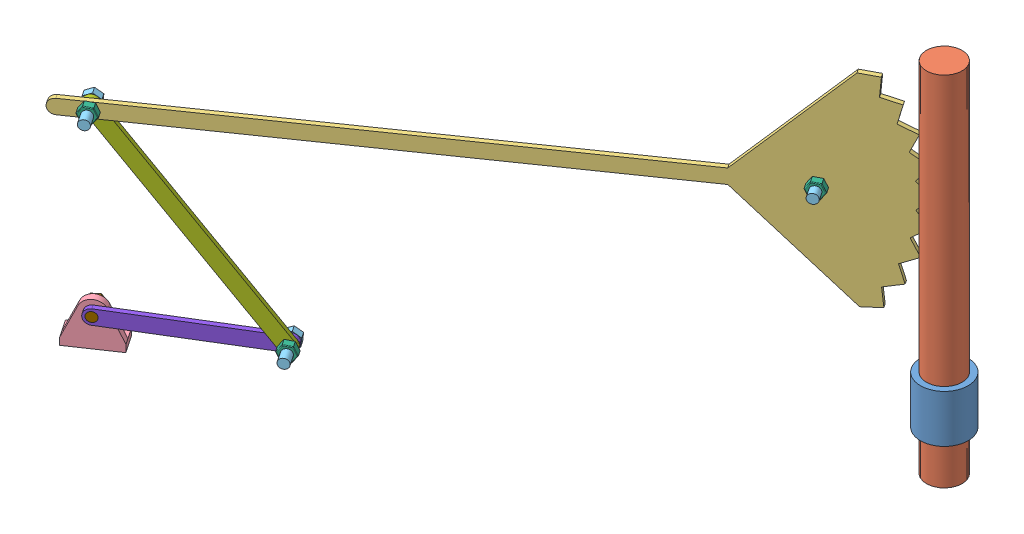
SolidWorks assembly 插齿机, configuration 默认. Lengths in mm.
Overall size (240.39 150 164.35).
14 component instances, 9 part files, 25 mates.
Components (placement in the parent):
- 轴承-1: 轴承 [默认] at (3.8746 0.457 0) size (20 20 20)
- 锤-1: 锤 [默认] at (0.769 48.5886 2.1018) x (0.828161 0 -0.560491) z (0.560491 0 0.828161) size (15 150 15)
- 齿轮杆-1: 齿轮杆 [默认] at (-166.317 72.2583 115.1839) x (0.828127 0.009016 -0.560468) z (0.560491 0 0.828161) size (268 84.85 2)
- 支座4-1: 支座4 [默认] at (-28.3419 73.7666 20.5963) x (-0.828161 0 0.560491) z (-0.560491 0 -0.828161) size (20 18 9)
- 螺钉4,12-1: 螺钉4,12 [默认] at (-30.0233 73.7666 18.1118) x (-0.828161 0 0.560491) z (-0.560491 0 -0.828161) size (6.28 6.9 15)
- 螺母4-1: 螺母4 [默认] at (-27.2209 73.7666 22.2526) x (0.828161 0 -0.560491) z (0.560491 0 0.828161) size (6.9 6.3 3)
- 杆100-1: 杆100 [默认] at (-185.8528 30.2022 124.7831) x (0.496542 -0.800321 -0.336054) z (0.560491 0 0.828161) size (106 6 2)
- 杆60-1: 杆60 [默认] at (-175.7228 -7.7374 115.5122) x (0.827693 -0.033592 -0.560174) z (0.560491 0 0.828161) size (66 6 2)
- 螺钉4,12-2: 螺钉4,12 [默认] at (-211.6508 71.7831 142.2429) x (-0.828161 0 0.560491) z (-0.560491 0 -0.828161) size (6.28 6.9 15)
- 螺母4-2: 螺母4 [默认] at (-209.4088 71.7831 145.5555) x (0.828161 0 -0.560491) z (0.560491 0 0.828161) size (6.9 6.3 3)
- 螺母4-3: 螺母4 [默认] at (-160.8756 -8.249 110.2938) x (0.828151 0.004901 -0.560484) z (0.560491 0 0.828161) size (6.9 6.3 3)
- 螺钉4,12-3: 螺钉4,12 [默认] at (-163.1176 -8.249 106.9811) x (-0.828161 0 0.560491) z (-0.560491 0 -0.828161) size (6.28 6.9 15)
- 支座4-2: 支座4 [默认] at (-212.7792 -6.2334 140.5916) x (-0.828161 0 0.560491) z (-0.560491 0 -0.828161) size (20 18 9)
- 螺钉4-3-1: 螺钉4-3 [默认] at (-214.4607 -6.2334 138.1071) x (-0.828161 0 0.560491) z (-0.560491 0 -0.828161) size (6.91 6.21 8)
Mates (geometry in assembly coordinates):
- 同心1: concentric: cylinder of 轴承-1 through (3.8746 10.457 0) axis (0 -1 0) radius 7.5; cylinder of 锤-1 through (3.8746 123.5886 0) axis (0 1 0) radius 7.5
- 重合1: coincident: plane of 锤-1 through (0.769 48.5886 2.1018) normal (0.560491 0 0.828161); plane of 齿轮杆-1 through (-166.317 72.2583 115.1839) normal (0.560491 0 0.828161)
- 重合3: coincident: line of 锤-1 through (1.2437 74.0886 0.5731) axis (0.560491 0 0.828161); plane of 齿轮杆-1
- 重合4: coincident: plane of 齿轮杆-1 through (-109.0476 -133.0111 75.2171) normal (-0.560491 0 -0.828161); plane of 支座4-1 through (-28.3419 73.7666 20.5963) normal (0.560491 0 0.828161)
- 同心2: concentric: cylinder of 支座4-1 through (-30.0233 73.7666 18.1118) axis (0.560491 0 0.828161) radius 2; cylinder of 螺钉4,12-1 through (-23.2974 73.7666 28.0497) axis (-0.560491 0 -0.828161) radius 2
- 同心3: concentric: cylinder of 齿轮杆-1 through (-27.2209 73.7666 22.2526) axis (-0.560491 0 -0.828161) radius 2; cylinder of 螺钉4,12-1 through (-23.2974 73.7666 28.0497) axis (-0.560491 0 -0.828161) radius 2
- 重合5: coincident: plane of 支座4-1 through (-30.0233 73.7666 18.1118) normal (-0.560491 0 -0.828161); plane of 螺钉4,12-1 through (-30.2711 70.3154 18.2795) normal (0.560491 0 0.828161)
- 重合6: coincident: plane of 齿轮杆-1 through (-107.9266 -133.0111 76.8734) normal (0.560491 0 0.828161); plane of 螺母4-1 through (-26.0302 70.6149 21.4468) normal (-0.560491 0 -0.828161)
- 同心4: concentric: cylinder of 螺钉4,12-1 through (-23.2974 73.7666 28.0497) axis (-0.560491 0 -0.828161) radius 2; cylinder of 螺母4-1 through (-25.5394 73.7666 24.7371) axis (-0.560491 0 -0.828161) radius 2
- 重合7: coincident: plane of 齿轮杆-1 through (-109.0476 -133.0111 75.2171) normal (-0.560491 0 -0.828161); plane of 杆100-1 through (-210.5298 71.7831 143.8992) normal (0.560491 0 0.828161)
- 重合8: coincident: plane of 杆100-1 through (-211.6508 71.7831 142.2429) normal (-0.560491 0 -0.828161); plane of 杆60-1 through (-211.6582 -6.2334 142.2479) normal (0.560491 0 0.828161)
- 同心5: concentric: cylinder of 杆100-1 through (-210.5298 71.7831 143.8992) axis (-0.560491 0 -0.828161) radius 2; cylinder of 螺钉4,12-2 through (-204.9249 71.7831 152.1808) axis (-0.560491 0 -0.828161) radius 2
- 同心6: concentric: cylinder of 齿轮杆-1 through (-209.4088 71.7831 145.5555) axis (-0.560491 0 -0.828161) radius 2; cylinder of 螺钉4,12-2 through (-204.9249 71.7831 152.1808) axis (-0.560491 0 -0.828161) radius 2
- 重合9: coincident: plane of 杆100-1 through (-211.6508 71.7831 142.2429) normal (-0.560491 0 -0.828161); plane of 螺钉4,12-2 through (-211.8986 68.3319 142.4106) normal (0.560491 0 0.828161)
- 重合10: coincident: plane of 齿轮杆-1 through (-107.9266 -133.0111 76.8734) normal (0.560491 0 0.828161); plane of 螺母4-2 through (-208.2182 68.6314 144.7497) normal (-0.560491 0 -0.828161)
- 同心7: concentric: cylinder of 螺钉4,12-2 through (-204.9249 71.7831 152.1808) axis (-0.560491 0 -0.828161) radius 2; cylinder of 螺母4-2 through (-207.7274 71.7831 148.04) axis (-0.560491 0 -0.828161) radius 2
- 同心8: concentric: cylinder of 杆60-1 through (-161.9966 -8.249 108.6374) axis (-0.560491 0 -0.828161) radius 2; cylinder of 螺钉4,12-3 through (-156.3917 -8.249 116.919) axis (-0.560491 0 -0.828161) radius 2
- 同心9: concentric: cylinder of 杆100-1 through (-160.8756 -8.249 110.2938) axis (-0.560491 0 -0.828161) radius 2; cylinder of 螺钉4,12-3 through (-156.3917 -8.249 116.919) axis (-0.560491 0 -0.828161) radius 2
- 重合11: coincident: plane of 杆60-1 through (-212.7792 -6.2334 140.5916) normal (-0.560491 0 -0.828161); plane of 螺钉4,12-3 through (-163.3654 -11.7001 107.1488) normal (0.560491 0 0.828161)
- 同心10: concentric: cylinder of 螺母4-3 through (-159.1942 -8.249 112.7782) axis (-0.560491 0 -0.828161) radius 2; cylinder of 螺钉4,12-3 through (-156.3917 -8.249 116.919) axis (-0.560491 0 -0.828161) radius 2
- 重合12: coincident: plane of 杆100-1 through (-210.5298 71.7831 143.8992) normal (0.560491 0 0.828161); plane of 螺母4-3 through (-159.6722 -11.3936 109.4793) normal (-0.560491 0 -0.828161)
- 重合13: coincident: plane of 杆60-1 through (-212.7792 -6.2334 140.5916) normal (-0.560491 0 -0.828161); plane of 支座4-2 through (-212.7792 -6.2334 140.5916) normal (0.560491 0 0.828161)
- 同心11: concentric: cylinder of 杆60-1 through (-211.6582 -6.2334 142.2479) axis (-0.560491 0 -0.828161) radius 2; cylinder of 支座4-2 through (-214.4607 -6.2334 138.1071) axis (0.560491 0 0.828161) radius 2
- 重合14: coincident: plane of 支座4-2 through (-214.4607 -6.2334 138.1071) normal (-0.560491 0 -0.828161); plane of 螺钉4-3-1 through (-215.7339 -9.3377 138.9688) normal (0.560491 0 0.828161)
- 同心12: concentric: cylinder of 支座4-2 through (-214.4607 -6.2334 138.1071) axis (0.560491 0 0.828161) radius 2; cylinder of 螺钉4-3-1 through (-211.6582 -6.2334 142.2479) axis (-0.560491 0 -0.828161) radius 2
